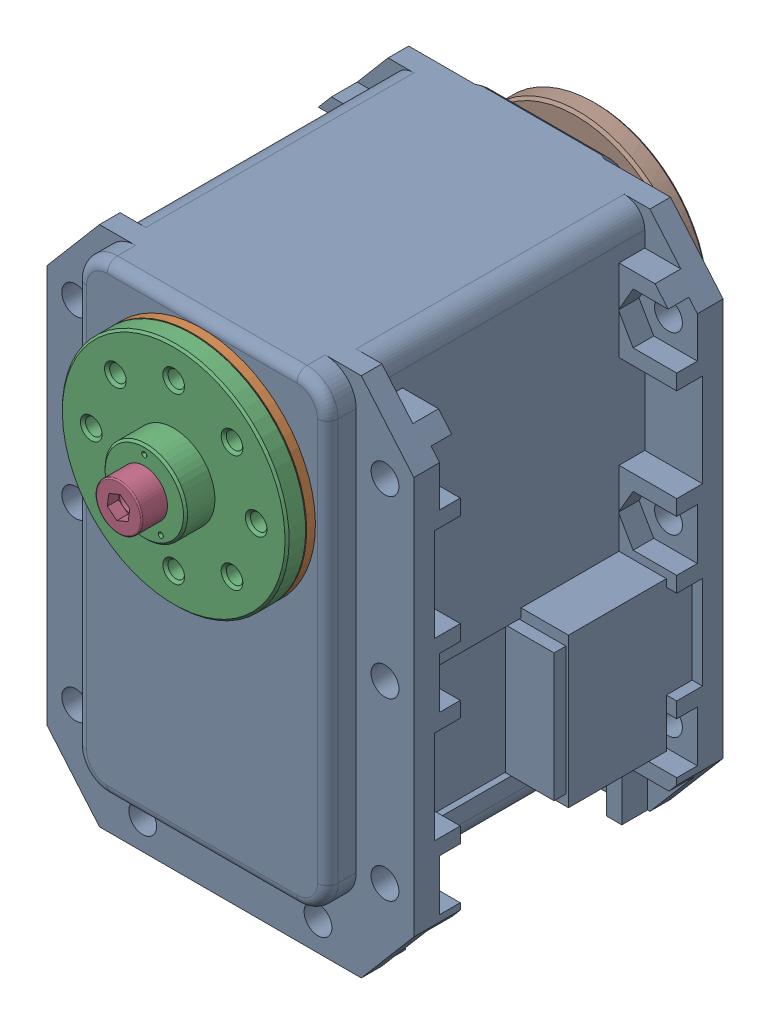
SolidWorks assembly MX-28(U)-6, configuration Default. Lengths in mm.
Overall size (35.6 54.13 48.5).
8 component instances, 7 part files, 0 mates.
Components (placement in the parent):
- dynamixel_x28series(U)-1: dynamixel_x28series(U) [Default] at origin size (35.6 50.71 41.85)
- trust_washer(U)-1: trust_washer(U) [Default] at (0 0 18.6) x (-0.666375 -0.745617 0) z (0.745617 -0.666375 0) size (22 0.85 22)
- HN07-N101(U)-1: HN07-N101(U) [Default] at (0 0 18.5) x (1 0 0) z (0 -1 0) size (22 5.85 22)
- WB_M2.5x8-1: WB_M2.5x8 [Default] at (0 0 25.85) x (0 0 -1) z (-0.991137 0.132843 0) size (10.5 4.5 4.5)
- WB_M2.5x8-2: WB_M2.5x8 [Default] at (0 0 -22.65) x (0 0 1) z (-0.936501 0.350665 0) size (10.5 4.5 4.5)
- RX28-CAP-1: RX28-CAP [Default] at (0 0 -20.35) x (-0.995735 -0.092256 0) z (0 0 -1) size (7.2 7.2 1.8)
- MF106ZZ-1: MF106ZZ [Default] at (0 0 -20.35) x (0.888333 -0.4592 0) z (-0.4592 -0.888333 0) size (11.2 3 11.2)
- HN07-i101-1: HN07-i101 [Default] at (0 0 -20.5) x (1 0 0) z (0 1 0) size (22 3.05 22)
